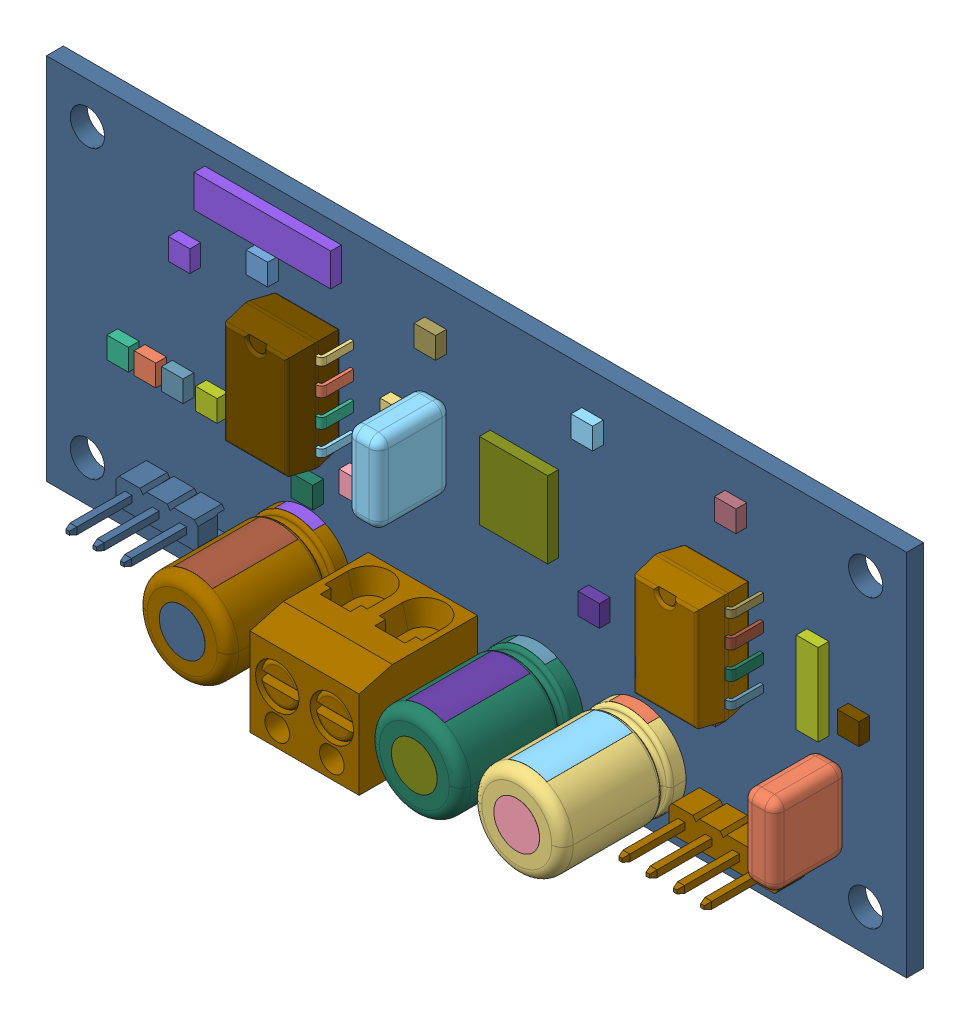
SolidWorks assembly servo control, configuration Standard. Lengths in mm.
Overall size (80.01 34.29 16.01).
65 component instances, 64 part files, 0 mates.
Components (placement in the parent):
- PPP5f11e933c2ba9.stp-1: PPP5f11e933c2ba9.stp [Standard] at origin size (80.01 34.29 16.01)
  - CAPPRD500W45D850H1150P001.stp-1: CAPPRD500W45D850H1150P001.stp [Standard] at (55.245 5.715 1.57) x (0 -1 0) z (0 0 1) size (0.45 0.45 2.54)
  - CAPPRD500W45D850H1150P004.stp-1: CAPPRD500W45D850H1150P004.stp [Standard] at (55.245 5.715 1.57) x (0 -1 0) z (0 0 1) size (0.41 3.61 1.15)
  - CAPPRD500W45D850H1150P005.stp-1: CAPPRD500W45D850H1150P005.stp [Standard] at (55.245 5.715 1.57) x (0 -1 0) z (0 0 1) size (8.5 8.5 11.5)
  - CAPPRD500W45D850H1150P002.stp-1: CAPPRD500W45D850H1150P002.stp [Standard] at (55.245 5.715 1.57) x (0 -1 0) z (0 0 1) size (4.25 4.25 0.01)
  - CAPPRD500W45D850H1150P003.stp-1: CAPPRD500W45D850H1150P003.stp [Standard] at (55.245 5.715 1.57) x (0 -1 0) z (0 0 1) size (0.41 3.61 7.96)
  - CAPPRD500W45D850H1150P.stp-1: CAPPRD500W45D850H1150P.stp [Standard] at (55.245 5.715 1.57) x (0 -1 0) z (0 0 1) size (0.45 0.45 2.54)
  - CAPPRD500W45D850H1150P006.stp-1: CAPPRD500W45D850H1150P006.stp [Standard] at (24.13 5.715 1.57) x (0 -1 0) z (0 0 1) size (0.45 0.45 2.54)
  - CAPPRD500W45D850H1150P007.stp-1: CAPPRD500W45D850H1150P007.stp [Standard] at (24.13 5.715 1.57) x (0 -1 0) z (0 0 1) size (0.41 3.61 1.15)
  - CAPPRD500W45D850H1150P008.stp-1: CAPPRD500W45D850H1150P008.stp [Standard] at (24.13 5.715 1.57) x (0 -1 0) z (0 0 1) size (8.5 8.5 11.5)
  - CAPPRD500W45D850H1150P009.stp-1: CAPPRD500W45D850H1150P009.stp [Standard] at (24.13 5.715 1.57) x (0 -1 0) z (0 0 1) size (4.25 4.25 0.01)
  - CAPPRD500W45D850H1150P010.stp-1: CAPPRD500W45D850H1150P010.stp [Standard] at (24.13 5.715 1.57) x (0 -1 0) z (0 0 1) size (0.41 3.61 7.96)
  - CAPPRD500W45D850H1150P011.stp-1: CAPPRD500W45D850H1150P011.stp [Standard] at (24.13 5.715 1.57) x (0 -1 0) z (0 0 1) size (0.45 0.45 2.54)
  - CAPPRD500W45D850H1150P012.stp-1: CAPPRD500W45D850H1150P012.stp [Standard] at (45.72 5.715 1.57) x (0 -1 0) z (0 0 1) size (0.45 0.45 2.54)
  - CAPPRD500W45D850H1150P013.stp-1: CAPPRD500W45D850H1150P013.stp [Standard] at (45.72 5.715 1.57) x (0 -1 0) z (0 0 1) size (0.41 3.61 1.15)
  - CAPPRD500W45D850H1150P014.stp-1: CAPPRD500W45D850H1150P014.stp [Standard] at (45.72 5.715 1.57) x (0 -1 0) z (0 0 1) size (8.5 8.5 11.5)
  - CAPPRD500W45D850H1150P015.stp-1: CAPPRD500W45D850H1150P015.stp [Standard] at (45.72 5.715 1.57) x (0 -1 0) z (0 0 1) size (4.25 4.25 0.01)
  - CAPPRD500W45D850H1150P016.stp-1: CAPPRD500W45D850H1150P016.stp [Standard] at (45.72 5.715 1.57) x (0 -1 0) z (0 0 1) size (0.41 3.61 7.96)
  - CAPPRD500W45D850H1150P017.stp-1: CAPPRD500W45D850H1150P017.stp [Standard] at (45.72 5.715 1.57) x (0 -1 0) z (0 0 1) size (0.45 0.45 2.54)
  - CAPRR500W50L750T300H680P001.stp-1: CAPRR500W50L750T300H680P001.stp [Standard] at (73.025 10.795 1.57) x (0 -1 0) z (0 0 1) size (0.5 0.5 6.8)
  - CAPRR500W50L750T300H680P002.stp-1: CAPRR500W50L750T300H680P002.stp [Standard] at (73.025 10.795 1.57) x (0 -1 0) z (0 0 1) size (7.5 3 6.8)
  - CAPRR500W50L750T300H680P.stp-1: CAPRR500W50L750T300H680P.stp [Standard] at (73.025 10.795 1.57) x (0 -1 0) z (0 0 1) size (0.5 0.5 6.8)
  - CAPRR500W50L750T300H680P003.stp-1: CAPRR500W50L750T300H680P003.stp [Standard] at (36.195 21.59 1.57) x (0 1 0) z (0 0 1) size (0.5 0.5 6.8)
  - CAPRR500W50L750T300H680P004.stp-1: CAPRR500W50L750T300H680P004.stp [Standard] at (36.195 21.59 1.57) x (0 1 0) z (0 0 1) size (7.5 3 6.8)
  - CAPRR500W50L750T300H680P005.stp-1: CAPRR500W50L750T300H680P005.stp [Standard] at (36.195 21.59 1.57) x (0 1 0) z (0 0 1) size (0.5 0.5 6.8)
  - Component_1.stp-1: Component_1.stp [Standard] at (71.755 19.685 1.57) x (0 1 0) z (0 0 1) size (7.62 2.03 1)
  - Component_2.stp-1: Component_2.stp [Standard] at (21.082 31.242 1.57) x (-1 0 0) z (0 0 1) size (12.7 3.05 1)
  - DIP762W45P254L1015H533Q8P008.stp-1: DIP762W45P254L1015H533Q8P008.stp [Standard] at (62.865 20.32 1.57) x (0 -1 0) z (0 0 1) size (10.15 6.49 5.1)
  - DIP762W45P254L1015H533Q8P001.stp-1: DIP762W45P254L1015H533Q8P001.stp [Standard] at (62.865 20.32 1.57) x (0 -1 0) z (0 0 1) size (0.95 0.57 3.1)
  - DIP762W45P254L1015H533Q8P006.stp-1: DIP762W45P254L1015H533Q8P006.stp [Standard] at (62.865 20.32 1.57) x (0 -1 0) z (0 0 1) size (0.95 0.57 3.1)
  - DIP762W45P254L1015H533Q8P007.stp-1: DIP762W45P254L1015H533Q8P007.stp [Standard] at (62.865 20.32 1.57) x (0 -1 0) z (0 0 1) size (0.7 0.57 3.1)
  - DIP762W45P254L1015H533Q8P003.stp-1: DIP762W45P254L1015H533Q8P003.stp [Standard] at (62.865 20.32 1.57) x (0 -1 0) z (0 0 1) size (0.7 0.57 3.1)
  - DIP762W45P254L1015H533Q8P004.stp-1: DIP762W45P254L1015H533Q8P004.stp [Standard] at (62.865 20.32 1.57) x (0 -1 0) z (0 0 1) size (0.7 0.57 3.1)
  - DIP762W45P254L1015H533Q8P005.stp-1: DIP762W45P254L1015H533Q8P005.stp [Standard] at (62.865 20.32 1.57) x (0 -1 0) z (0 0 1) size (0.95 0.57 3.1)
  - DIP762W45P254L1015H533Q8P002.stp-1: DIP762W45P254L1015H533Q8P002.stp [Standard] at (62.865 20.32 1.57) x (0 -1 0) z (0 0 1) size (0.95 0.57 3.1)
  - DIP762W45P254L1015H533Q8P.stp-1: DIP762W45P254L1015H533Q8P.stp [Standard] at (62.865 20.32 1.57) x (0 -1 0) z (0 0 1) size (0.7 0.57 3.1)
  - DIP762W45P254L1015H533Q8P009.stp-1: DIP762W45P254L1015H533Q8P009.stp [Standard] at (24.765 21.59 1.57) x (0 -1 0) z (0 0 1) size (10.15 6.49 5.1)
  - DIP762W45P254L1015H533Q8P010.stp-1: DIP762W45P254L1015H533Q8P010.stp [Standard] at (24.765 21.59 1.57) x (0 -1 0) z (0 0 1) size (0.95 0.57 3.1)
  - DIP762W45P254L1015H533Q8P011.stp-1: DIP762W45P254L1015H533Q8P011.stp [Standard] at (24.765 21.59 1.57) x (0 -1 0) z (0 0 1) size (0.95 0.57 3.1)
  - DIP762W45P254L1015H533Q8P012.stp-1: DIP762W45P254L1015H533Q8P012.stp [Standard] at (24.765 21.59 1.57) x (0 -1 0) z (0 0 1) size (0.7 0.57 3.1)
  - DIP762W45P254L1015H533Q8P013.stp-1: DIP762W45P254L1015H533Q8P013.stp [Standard] at (24.765 21.59 1.57) x (0 -1 0) z (0 0 1) size (0.7 0.57 3.1)
  - DIP762W45P254L1015H533Q8P014.stp-1: DIP762W45P254L1015H533Q8P014.stp [Standard] at (24.765 21.59 1.57) x (0 -1 0) z (0 0 1) size (0.7 0.57 3.1)
  - DIP762W45P254L1015H533Q8P015.stp-1: DIP762W45P254L1015H533Q8P015.stp [Standard] at (24.765 21.59 1.57) x (0 -1 0) z (0 0 1) size (0.95 0.57 3.1)
  - DIP762W45P254L1015H533Q8P016.stp-1: DIP762W45P254L1015H533Q8P016.stp [Standard] at (24.765 21.59 1.57) x (0 -1 0) z (0 0 1) size (0.95 0.57 3.1)
  - DIP762W45P254L1015H533Q8P017.stp-1: DIP762W45P254L1015H533Q8P017.stp [Standard] at (24.765 21.59 1.57) x (0 -1 0) z (0 0 1) size (0.7 0.57 3.1)
  - 1.stp-1: 1.stp [Standard] at (65.405 4.445 1.57) size (10.16 2.5 11.2)
  - 1001.stp-1: 1001.stp [Standard] at (12.7 5.08 1.57) size (7.62 2.5 11.2)
  - Component_3.stp-1: Component_3.stp [Standard] at (62.23 13.335 1.57) size (2 2 1)
  - Component_004.stp-1: Component_004.stp [Standard] at (36.195 29.845 1.57) x (-1 0 0) z (0 0 1) size (2 2 1)
  - Component_005.stp-1: Component_005.stp [Standard] at (64.135 29.845 1.57) x (-1 0 0) z (0 0 1) size (2 2 1)
  - Component_006.stp-1: Component_006.stp [Standard] at (12.7 14.605 1.57) x (0 1 0) z (0 0 1) size (2 2 1)
  - Component_007.stp-1: Component_007.stp [Standard] at (24.765 12.065 1.57) size (2 2 1)
  - Component_4.stp-1: Component_4.stp [Standard] at (44.45 19.05 1.57) x (-1 0 0) z (0 0 1) size (6.35 7.11 1)
  - Component_008.stp-1: Component_008.stp [Standard] at (51.435 15.875 1.57) x (0 -1 0) z (0 0 1) size (2 2 1)
  - Component_009.stp-1: Component_009.stp [Standard] at (75.565 18.415 1.57) x (0 1 0) z (0 0 1) size (2 2 1)
  - Component_010.stp-1: Component_010.stp [Standard] at (20.574 27.94 1.57) x (-1 0 0) z (0 0 1) size (2 2 1)
  - Component_011.stp-1: Component_011.stp [Standard] at (10.16 14.605 1.57) x (0 -1 0) z (0 0 1) size (2 2 1)
  - Component_012.stp-1: Component_012.stp [Standard] at (33.02 22.225 1.57) x (0 1 0) z (0 0 1) size (2 2 1)
  - Component_013.stp-1: Component_013.stp [Standard] at (29.21 14.605 1.57) size (2 2 1)
  - Component_014.stp-1: Component_014.stp [Standard] at (50.8 29.845 1.57) x (-1 0 0) z (0 0 1) size (2 2 1)
  - Component_015.stp-1: Component_015.stp [Standard] at (7.62 14.605 1.57) x (0 -1 0) z (0 0 1) size (2 2 1)
  - Component_016.stp-1: Component_016.stp [Standard] at (15.875 14.605 1.57) x (0 1 0) z (0 0 1) size (2 2 1)
  - Component_017.stp-1: Component_017.stp [Standard] at (13.335 25.4 1.57) x (-1 0 0) z (0 0 1) size (2 2 1)
  - HI_237-132.stp-1: HI_237-132.stp [Standard] at (34.925 4.445 1.57) x (-1 0 0) z (0 0 1) size (10.16 9 15.5)
  - Component_Component.stp-1: Component_Component.stp [Standard] at origin size (80.01 34.29 1.57)
